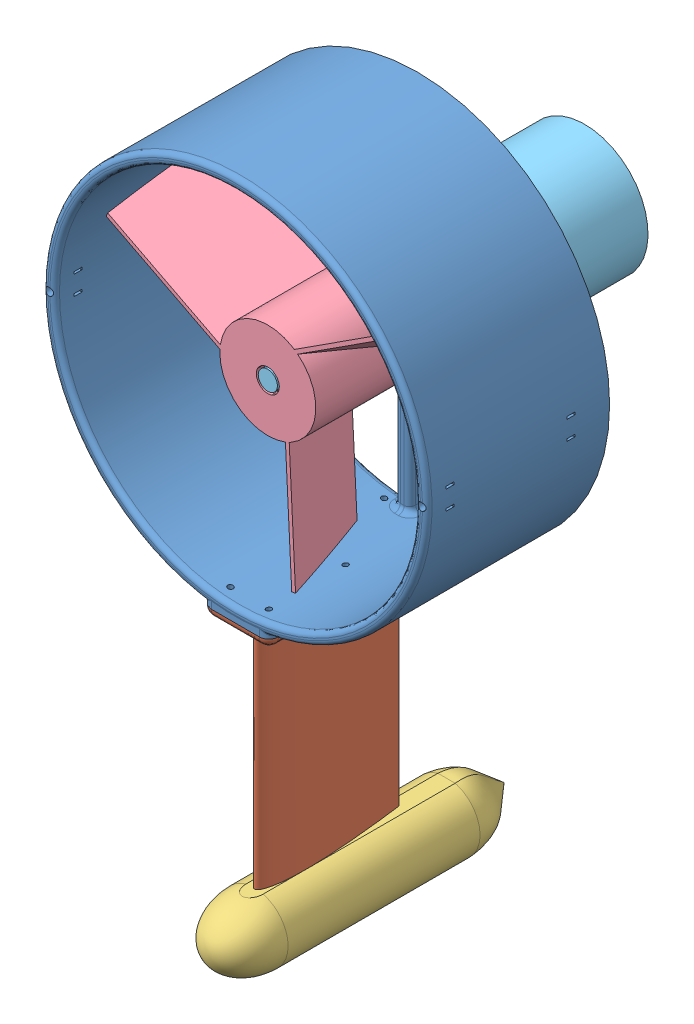
SolidWorks assembly duct assembly, configuration Default. Lengths in mm.
Overall size (200 360.69 196.95).
5 component instances, 5 part files, 20 mates.
Components (placement in the parent):
- duct-1: duct [Default] at (-43.8289 101 122.3444) x (-1 0 0) z (0 0 1) size (200 201 95.36)
- mast - naca 0012-1: mast - naca 0012 [Default] at (-43.8289 -62.5 207.2939) x (0 0 -1) z (-1 0 0) size (95 125 35)
- bulb-1: bulb [Default] at (-43.8289 -141.9115 157.2939) size (35.27 35.28 155)
- prop-1: prop [Default] at (-43.8289 101 150.3444) x (0.049734 -0.998762 0) z (-0.998762 -0.049734 0) size (143.38 50 164.92)
- Flipsky 66112 Motor-1: Flipsky 66112 Motor [Default] at (-43.8289 101 82.0944) x (-0.707107 -0.707107 0) z (0 0 1) size (66 66 165)
Mates (geometry in assembly coordinates):
- Coincident1: coincident: plane of duct-1 through (43.8289 77.1171 122.3444) normal (0 0 -1); plane of ? through (43.8289 77.1171 122.3444) normal (0 0 1)
- Concentric1: concentric: circle of duct-1; circle of ?
- Concentric2: concentric: circle of duct-1; circle of ?
- Coincident2: coincident: plane of duct-1 through (43.8289 77.1171 124.3444) normal (0 0 1); plane of ? through (43.8289 77.1171 124.3444) normal (0 0 -1)
- Concentric3: concentric: circle of duct-1; circle of ?
- Coincident3: coincident: plane of duct-1 through (43.8289 77.1171 122.3444) normal (0 0 -1); plane of ? through (43.8289 77.1171 122.3444) normal (0 0 1)
- Concentric4: concentric: circle of duct-1; circle of ?
- Concentric9: concentric: circle of ?; circle of prop-1
- Distance1: distance = 8 mm: plane of prop-1 through (43.8289 77.1171 194.3444) normal (0 0 1); plane of ? through (43.8289 77.1171 202.3444) normal (0 0 1)
- Coincident4: coincident: plane of duct-1 through (-31.3289 0 212.2939) normal (0 -1 0); plane of mast - naca 0012-1 through (-43.634 0 207.2667) normal (0 1 0)
- Concentric11: concentric: cylinder of mast - naca 0012-1 through (-53.8289 0 209.7939) axis (0 -1 0) radius 2.25; circle of duct-1
- Concentric12: concentric: circle of mast - naca 0012-1; circle of duct-1
- Coincident5: coincident: plane of mast - naca 0012-1 through (-43.634 -125 207.2667) normal (0 -1 0); plane of bulb-1 through (-48.3289 -125 107.2939) normal (0 1 0)
- Concentric13: concentric: circle of bulb-1; circle of mast - naca 0012-1
- Concentric14: concentric: circle of bulb-1; circle of mast - naca 0012-1
- Concentric15: concentric: cylinder of duct-1 through (56.1721 201.001 126.3444) axis (-0.707107 -0.707107 0) radius 2.25; cylinder of Flipsky 66112 Motor-1 through (-20.4944 124.3345 126.3444) axis (-0.707107 -0.707107 0) radius 1.4
- Concentric16: concentric: cylinder of duct-1 through (56.1721 0.999 126.3444) axis (-0.707107 0.707107 0) radius 2.25; cylinder of Flipsky 66112 Motor-1 through (-20.4944 77.6655 126.3444) axis (-0.707107 0.707107 0) radius 1.4
- Distance2: distance = 50 mm: plane of prop-1 through (-43.8289 101 150.3444) normal (0 0 -1); plane of Flipsky 66112 Motor-1 through (-43.8289 101 200.3444) normal (0 0 1)
- Concentric17: concentric: circle of prop-1; circle of Flipsky 66112 Motor-1
- Coincident6: coincident: plane of duct-1 through (-31.3289 0 212.2939) normal (0 -1 0); plane of assembly through (0 0 0) normal (0 1 0)
